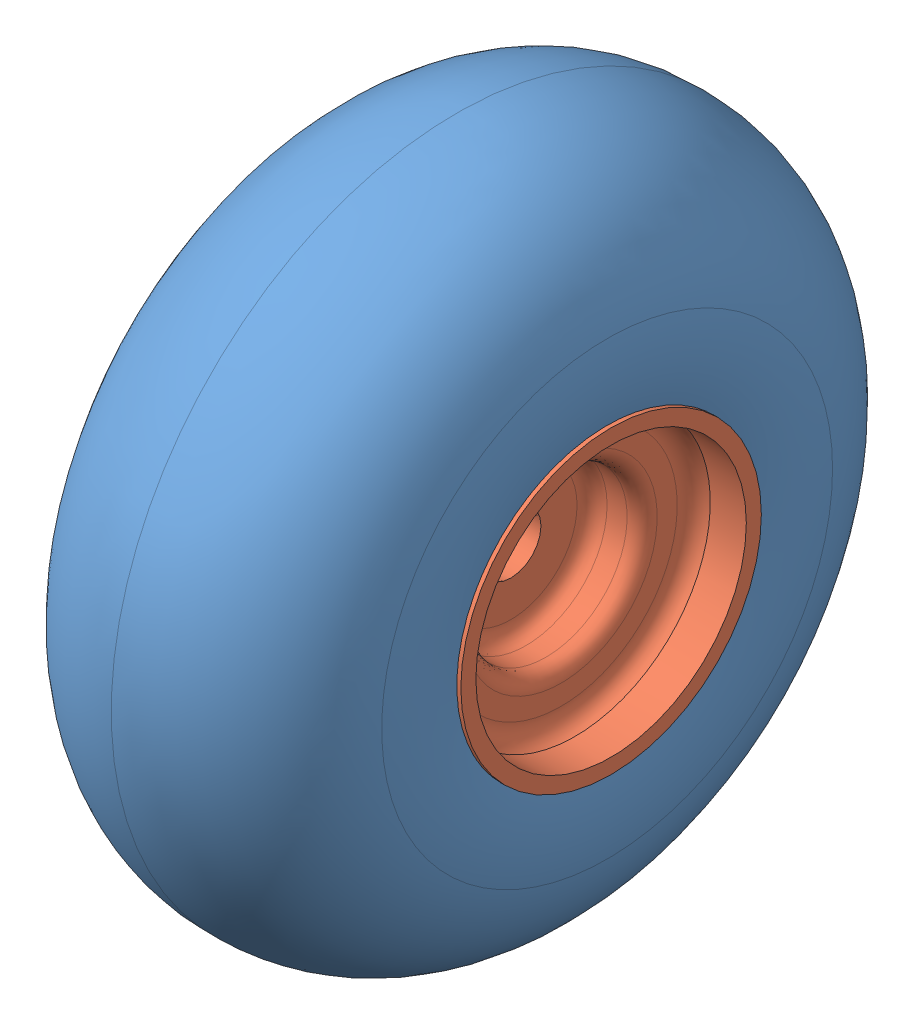
SolidWorks assembly 5.00-5 wheel and tire assembly, configuration Default. Lengths in mm.
Overall size (130.34 292.13 292.13).
2 component instances, 2 part files, 2 mates.
Components (placement in the parent):
- Tire 5.00-5-1: Tire 5.00-5 [Default] at (67.5419 180.3345 364.7938) size (130.34 292.13 292.13)
- Wheel 5.00-5-1: Wheel 5.00-5 [Default] at (48.0472 180.3345 364.7938) size (127 127 127)
Mates (geometry in assembly coordinates):
- Tangent1: tangent aligned: torus of Tire 5.00-5-1; plane of Wheel 5.00-5-1 through (132.7139 237.4845 364.7938) normal (1 0 0)
- Concentric2: concentric anti-aligned: cylinder of Tire 5.00-5-1 through (67.5419 180.3345 364.7938) axis (1 0 0) radius 63.5; cylinder of Wheel 5.00-5-1 through (48.0472 180.3345 364.7938) axis (-1 0 0) radius 63.5
